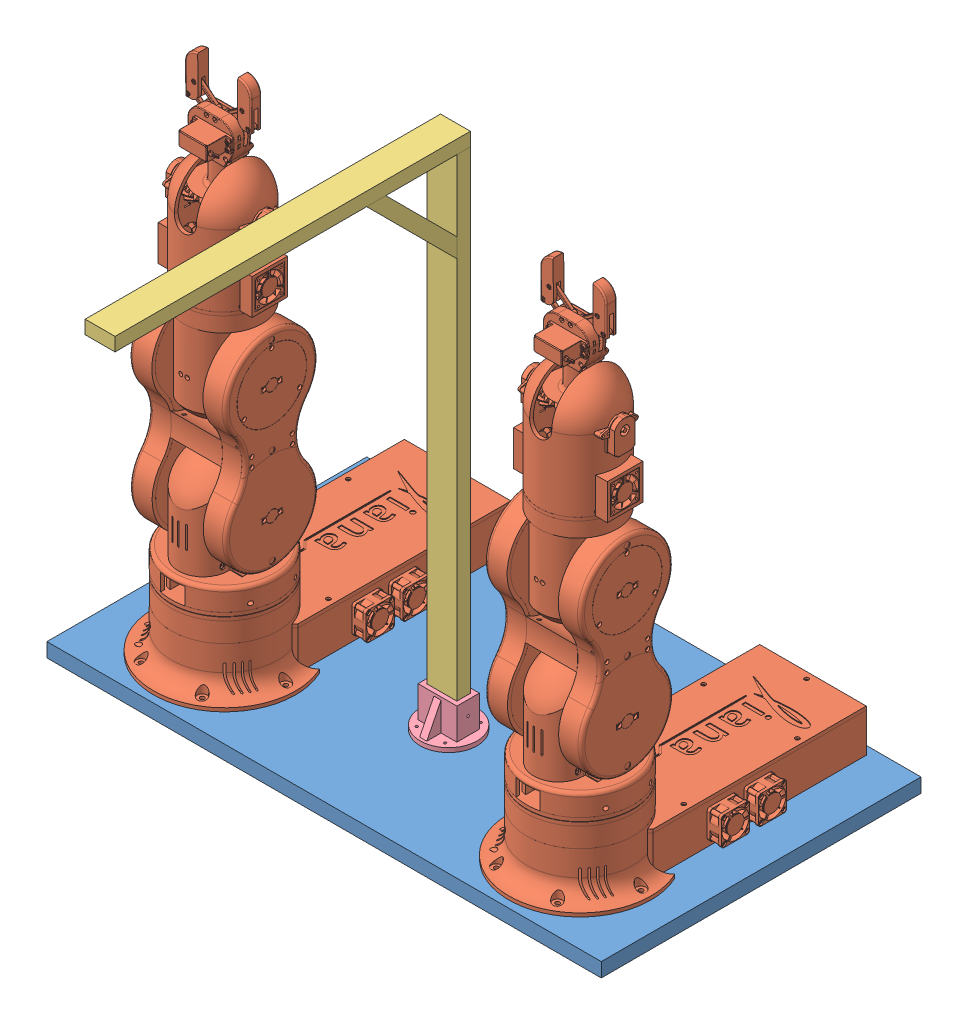
SolidWorks assembly mesa2, configuration Predeterminado. Lengths in mm.
Overall size (780 755 765.2).
5 component instances, 4 part files, 12 mates.
Components (placement in the parent):
- mesa2-1: mesa2 [Predeterminado] at origin size (780 20 450)
- URDF-1: URDF [Predeterminado] at (-250 20 115) x (0 0 1) z (0 1 0) size (427.94 200 721.22)
- URDF-2: URDF [Predeterminado] at (250 20 115) x (0 0 1) z (0 1 0) size (427.94 200 721.22)
- soporte-1: soporte [Predeterminado] at (0 26 49.7) x (0 0 1) z (-1 0 0) size (500 729 42)
- UnionSoporte-1: UnionSoporte [Predeterminado] at (-0.3 20 49.4) x (0 0 -1) z (1 0 0) size (80 50 80)
Mates (geometry in assembly coordinates):
- Distancia1: distance = 500 mm: cylinder of URDF-1 through (-250 98.0387 115) axis (0 1 0) radius 100; cylinder of URDF-2 through (250 98.0387 115) axis (0 1 0) radius 100
- Coincidente1: coincident anti-aligned: plane of mesa2-1 through (0 20 0) normal (0 1 0); plane of URDF-2 through (250 20 115) normal (0 -1 0)
- Coincidente3: coincident aligned: line of URDF-1 through (-175 20 -212.9437) axis (-1 0 0); line of URDF-2 through (325 20 -212.9437) axis (-1 0 0)
- Coincidente12: coincident: point of mesa2-1; unknown of URDF-1
- Paralelo1: parallel aligned: plane of mesa2-1 through (-390 20 225) normal (-1 0 0); plane of URDF-1 through (-325 75 -212.9437) normal (-1 0 0)
- Distancia2: distance = 10 mm: unknown of URDF-1; plane of mesa2-1 through (390 20 225) normal (0 0 1)
- Distancia4: distance = 315.2 mm aligned: plane of soporte-1 through (0 26 540.2) normal (0 0 1); plane of mesa2-1 through (390 20 225) normal (0 0 1)
- Coincidente18: coincident: plane of assembly; point of mesa2-1; plane of soporte-1 through (0 26 49.7) normal (-1 0 0)
- Coincidente19: coincident anti-aligned: plane of soporte-1 through (0 26 49.7) normal (0 -1 0); plane of UnionSoporte-1 through (-0.3 26 49.4) normal (0 1 0)
- Coincidente20: coincident anti-aligned: plane of soporte-1 through (-21 736 59.2) normal (0 0 1); plane of UnionSoporte-1 through (21 70 59.2) normal (0 0 -1)
- Coincidente21: coincident anti-aligned: plane of soporte-1 through (21 736 59.2) normal (1 0 0); plane of UnionSoporte-1 through (21 70 59.2) normal (-1 0 0)
- Coincidente22: coincident anti-aligned: plane of mesa2-1 through (0 20 0) normal (0 1 0); plane of UnionSoporte-1 through (-0.3 20 49.4) normal (0 -1 0)
